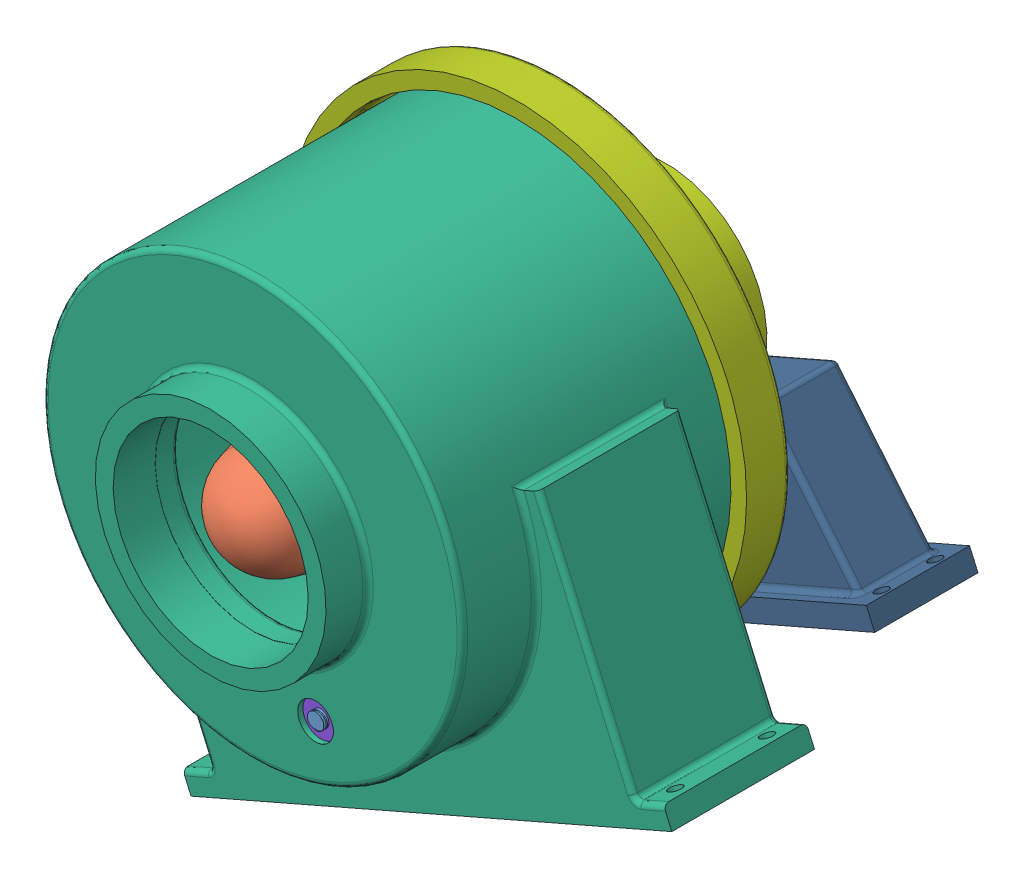
SolidWorks assembly Throttle System Assembly, configuration Default. Lengths in mm.
Overall size (324.2 313.57 270.19).
12 component instances, 11 part files, 36 mates.
Components (placement in the parent):
- thread-1: thread [Default] at origin size (8.16 9.2 206.05)
- cone-1: cone [Default] at (-30.4574 69.8483 90.424) x (-0.399703 0.916645 0) z (0 0 1) size (174.69 116.84 102.74)
- holder-1: holder [Default] at (0 0 100.584) x (0.434513 -0.900666 0) z (0 0 1) size (22.28 22.28 15.21)
- bushing-1: bushing [Default] at (-60.9148 139.6966 100.584) x (0.650956 0.759116 0) z (0 0 1) size (12.7 12.7 12.7)
- non-threaded_rod-2: non-threaded_rod [Default] at (-60.9148 139.6966 39.624) x (-0.180756 0.983528 0) z (0 0 1) size (7.95 7.95 135.64)
- Bracket_Front-1: Bracket_Front [Default] at (-30.4574 69.8483 177.8) x (0.916645 0.399703 0) z (0 0 1) size (254 228.6 158.5)
- Bracket_Back-1: Bracket_Back [Default] at (-30.4574 69.8483 39.624) x (0.916645 0.399703 0) z (0 0 1) size (222.43 222.43 72.14)
- Bearing_Rough-1: Bearing_Rough [Default] at (0 0 30.988) x (0.047017 -0.998894 0) z (0 0 1) size (22.35 22.35 8.73)
- Bearing_Rough-2: Bearing_Rough [Default] at (0 0 166.5275) x (0.416534 -0.90912 0) z (0 0 1) size (22.35 22.35 8.73)
- coupler_Rough-1: coupler_Rough [Default] at (0 0 12.446) x (0.977782 0.209624 0) z (0 0 -1) size (18.8 18.8 24.89)
- stepper_stand-1: stepper_stand [Default] at (17.7945 -40.7971 -14.9569) x (-0.916645 -0.399703 0) z (0 0 -1) size (127 81.79 50)
- servo-2: servo [Default] at (-8.4773 19.4411 -40.4749) x (0.916645 0.399703 0) z (0.399703 -0.916645 0) size (42.29 56.98 42.42)
Mates (geometry in assembly coordinates):
- Coincident1: coincident: plane of thread-1 through (0 0 0) normal (0 0 1); plane of assembly through (0 0 0) normal (0 0 1)
- Coincident2: coincident: plane of thread-1 through (0 0 0) normal (0 1 0); plane of assembly through (0 0 0) normal (0 1 0)
- Coincident3: coincident: plane of thread-1 through (0 0 0) normal (1 0 0); plane of assembly through (0 0 0) normal (1 0 0)
- Concentric1: concentric: cylinder of cone-1 through (0 0 90.424) axis (0 0 1) radius 5.2197; cylinder of holder-1 through (0 0 106.8705) axis (0 0 -1) radius 3.9751
- Coincident4: coincident: plane of cone-1 through (-79.3512 48.5281 100.584) normal (0 0 1); plane of holder-1 through (0 0 100.584) normal (0 0 -1)
- Concentric2: concentric: cylinder of thread-1 through (0 0 177.8) axis (0 0 -1) radius 3.9751; cylinder of holder-1 through (0 0 106.8705) axis (0 0 -1) radius 3.9751
- Concentric3: concentric: cylinder of bushing-1 through (-60.9148 139.6966 95.504) axis (0 0 1) radius 3.9751; cylinder of non-threaded_rod-2 through (-60.9148 139.6966 175.26) axis (0 0 -1) radius 3.9751
- Concentric4: concentric: cylinder of bushing-1 through (-60.9148 139.6966 95.504) axis (0 0 1) radius 3.9751; cylinder of cone-1 through (-60.9148 139.6966 90.424) axis (0 0 1) radius 8.1026
- Coincident5: coincident: plane of bushing-1 through (-60.9148 139.6966 90.424) normal (0 0 1); plane of cone-1 through (-79.3512 48.5281 90.424) normal (0 0 -1)
- Parallel1: parallel: cylinder of thread-1 through (0 0 177.8) axis (0 0 -1) radius 3.9751; cylinder of non-threaded_rod-2 through (-60.9148 139.6966 175.26) axis (0 0 -1) radius 3.9751
- Concentric6: concentric: cylinder of non-threaded_rod-2 through (-60.9148 139.6966 175.26) axis (0 0 -1) radius 3.9751; cylinder of Bracket_Front-1 through (-60.9148 139.6966 39.624) axis (0 0 1) radius 4.0767
- Coincident8: coincident: plane of thread-1 through (0 0 177.8) normal (0 0 1); plane of Bracket_Front-1 through (-30.4574 69.8483 177.8) normal (0 0 1)
- Concentric7: concentric: cylinder of thread-1 through (0 0 177.8) axis (0 0 -1) radius 3.9751; cylinder of Bracket_Front-1 through (0 0 39.624) axis (0 0 1) radius 11.2141
- Concentric8: concentric: cylinder of thread-1 through (0 0 177.8) axis (0 0 -1) radius 3.9751; cylinder of Bracket_Back-1 through (0 0 79.248) axis (0 0 -1) radius 11.2776
- Concentric9: concentric: cylinder of non-threaded_rod-2 through (-60.9148 139.6966 175.26) axis (0 0 -1) radius 3.9751; cylinder of Bracket_Back-1 through (-60.9148 139.6966 49.784) axis (0 0 -1) radius 4.0767
- Concentric11: concentric: cylinder of Bracket_Front-1 through (0 0 39.624) axis (0 0 1) radius 11.2141; cylinder of Bearing_Rough-2 through (0 0 175.26) axis (0 0 -1) radius 11.176
- Coincident9: coincident: plane of Bracket_Front-1 through (0 0 175.26) normal (0 0 -1); plane of Bearing_Rough-2 through (0 0 175.26) normal (0 0 1)
- Concentric12: concentric: cylinder of Bracket_Back-1 through (0 0 79.248) axis (0 0 -1) radius 11.2776; cylinder of Bearing_Rough-1 through (0 0 39.7205) axis (0 0 -1) radius 11.176
- Coincident10: coincident: plane of Bracket_Back-1 through (0 0 30.988) normal (0 0 1); plane of Bearing_Rough-1 through (0 0 30.988) normal (0 0 -1)
- Coincident11: coincident: plane of thread-1 through (0 0 177.8) normal (0 0 1); plane of Bracket_Front-1 through (-30.4574 69.8483 177.8) normal (0 0 1)
- Coincident14: coincident: plane of thread-1 through (0 0 0) normal (0 0 -1); plane of coupler_Rough-1 through (0 0 0) normal (0 0 1)
- Concentric13: concentric: cylinder of thread-1 through (0 0 177.8) axis (0 0 -1) radius 3.9751; cylinder of coupler_Rough-1 through (0 0 0) axis (0 0 1) radius 3.9878
- Coincident20: coincident: plane of Bracket_Front-1 through (-30.4574 69.8483 39.624) normal (0 0 -1); plane of Bracket_Back-1 through (-30.4574 69.8483 39.624) normal (0 0 1)
- Concentric15: concentric: cylinder of coupler_Rough-1 through (0 0 -12.446) axis (0 0 1) radius 2.54; cylinder of servo-2 through (0 0 0) axis (0 0 -1) radius 2.5273
- Coincident29: coincident: plane of stepper_stand-1 through (-10.9056 -27.893 -23.9649) normal (-0.399703 0.916645 0); plane of servo-2 through (8.4773 -19.4411 -40.4749) normal (0.399703 -0.916645 0)
- Coincident30: coincident: plane of thread-1 through (0 0 0) normal (0 0 -1); plane of servo-2 through (0 0 0) normal (0 0 1)
- Coincident31: coincident: plane of stepper_stand-1 through (17.7945 -40.7971 -23.9649) normal (0 0 -1); plane of servo-2 through (27.8602 -10.9892 -23.9649) normal (0 0 1)
- Parallel2: parallel: plane of Bracket_Front-1 through (20.3049 -46.5655 177.8) normal (0.399703 -0.916645 0); plane of stepper_stand-1 through (-38.3819 -70.8348 -64.9569) normal (0.399703 -0.916645 0)
- Coincident34: coincident: plane of stepper_stand-1 through (-27.8131 10.881 -23.9649) normal (0.916645 0.399703 0); plane of servo-2 through (-10.9056 -27.893 -56.9849) normal (-0.916645 -0.399703 0)
- Concentric16: concentric: cylinder of thread-1 through (0 0 177.8) axis (0 0 -1) radius 3.9751; cylinder of holder-1 through (0 0 106.8705) axis (0 0 -1) radius 3.9751
- Lock2: lock: unknown of cone-1; unknown of bushing-1
- Lock3: lock: unknown of bushing-1; unknown of non-threaded_rod-2
- Lock4: lock: unknown of thread-1; unknown of holder-1
- Lock5: lock: unknown of Bracket_Back-1; unknown of coupler_Rough-1
- Lock6: lock: unknown of Bracket_Front-1; unknown of Bearing_Rough-2
- Lock7: lock: unknown of Bracket_Back-1; unknown of Bearing_Rough-1
